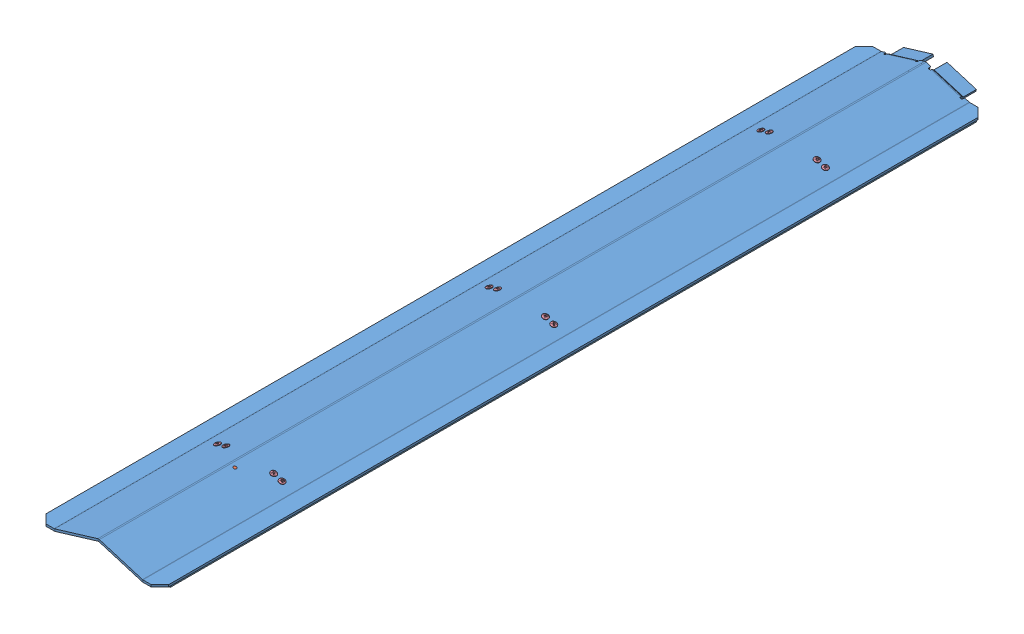
SolidWorks assembly GE-19226, configuration Default. Lengths in mm.
Overall size (177.8 23.82 1219.2).
20 component instances, 5 part files, 39 mates.
Components (placement in the parent):
- GE-19223-1: GE-19223 [Default] at origin size (177.8 22.23 1219.2)
  - GE-19223-1-1: GE-19223-1 [Default] at origin size (177.8 22.23 1219.2)
  - PEM-FH-832-6ZI-1: PEM-FH-832-6ZI [Default] at (7.1934 20.2237 419.1) x (-0.289806 -0.957086 0) z (-0.571052 0.172915 0.802496) size (9.53 6.02 6.02)
- GE-19224-1: GE-19224 [Default] at (0.0601 3.1126 390.525) x (1 -0.000064 0) z (0 0 1) size (106.54 12.92 31.75)
- GE-19224-2: GE-19224 [Default] at (0.0601 3.1126 -3.175) x (1 -0.000064 0) z (0 0 1) size (106.54 12.92 31.75)
- GE-19224-3: GE-19224 [Default] at (0.0601 3.1126 -396.875) x (1 -0.000064 0) z (0 0 1) size (106.54 12.92 31.75)
- rivet_.1563_.1875-.25-1: rivet_.1563_.1875-.25 [Default] at (47.0652 9.4775 390.525) x (-0.569603 0.172476 -0.80362) z (-0.289806 -0.957086 0) size (8.33 8.33 8.57)
- rivet_.1563_.1875-.25-2: rivet_.1563_.1875-.25 [Default] at (-47.0652 9.4775 390.525) x (-0.904542 -0.273895 -0.326781) z (0.289806 -0.957086 0) size (8.33 8.33 8.57)
- rivet_.1563_.1875-.25-3: rivet_.1563_.1875-.25 [Default] at (-34.9102 13.158 -3.175) x (-0.916013 -0.277369 0.289806) z (0.289806 -0.957086 0) size (8.33 8.33 8.57)
- rivet_.1563_.1875-.25-4: rivet_.1563_.1875-.25 [Default] at (-47.0652 9.4775 -3.175) x (-0.916013 -0.277369 0.289806) z (0.289806 -0.957086 0) size (8.33 8.33 8.57)
- rivet_.1563_.1875-.25-5: rivet_.1563_.1875-.25 [Default] at (34.9102 13.158 390.525) x (-0.284635 0.086188 0.954754) z (-0.289806 -0.957086 0) size (8.33 8.33 8.57)
- rivet_.1563_.1875-.25-6: rivet_.1563_.1875-.25 [Default] at (-34.9102 13.158 390.525) x (-0.852981 -0.258283 0.453557) z (0.289806 -0.957086 0) size (8.33 8.33 8.57)
- rivet_.1563_.1875-.25-7: rivet_.1563_.1875-.25 [Default] at (34.9102 13.158 -3.175) x (-0.728247 0.220513 -0.648868) z (-0.289806 -0.957086 0) size (8.33 8.33 8.57)
- rivet_.1563_.1875-.25-9: rivet_.1563_.1875-.25 [Default] at (47.0652 9.4775 -3.175) x (-0.856065 0.259217 -0.447167) z (-0.289806 -0.957086 0) size (8.33 8.33 8.57)
- rivet_.1563_.1875-.25-11: rivet_.1563_.1875-.25 [Default] at (47.0652 9.4775 -396.875) x (-0.934813 0.283061 -0.21448) z (-0.289806 -0.957086 0) size (8.33 8.33 8.57)
- rivet_.1563_.1875-.25-13: rivet_.1563_.1875-.25 [Default] at (34.9102 13.158 -396.875) x (-0.956866 0.289739 0.021408) z (-0.289806 -0.957086 0) size (8.33 8.33 8.57)
- rivet_.1563_.1875-.25-15: rivet_.1563_.1875-.25 [Default] at (-34.9102 13.158 -396.875) x (-0.945179 -0.2862 0.157243) z (0.289806 -0.957086 0) size (8.33 8.33 8.57)
- rivet_.1563_.1875-.25-17: rivet_.1563_.1875-.25 [Default] at (-47.0652 9.4775 -396.875) x (-0.897265 -0.271692 0.347994) z (0.289806 -0.957086 0) size (8.33 8.33 8.57)
- Hook_1_46-1: Hook_1_46 [Default] at (76.2 -1.5875 10.5486) x (0 0 -1) z (1 0 0) size (1168.4 1.59 25.4)
- Hook_1_46-2: Hook_1_46 [Default] at (-76.2 -1.5875 10.5486) x (0 0 1) z (-1 0 0) size (1168.4 1.59 25.4)
Mates (geometry in assembly coordinates):
- Concentric3: concentric: cylinder of GE-19223-1/GE-19223-1-1 through (-46.6971 8.262 390.525) axis (-0.289806 0.957086 0) radius 1.9844; cylinder of GE-19224-1 through (-45.8168 5.3545 390.525) axis (-0.289806 0.957086 0) radius 1.9844
- Coincident1: coincident: plane of GE-19223-1/GE-19223-1-1 through (-63.5 0 609.6) normal (0.289806 -0.957086 0); plane of GE-19224-1 through (-53.2092 3.1161 374.65) normal (-0.289806 0.957086 0)
- Parallel2: parallel: plane of GE-19223-1/GE-19223-1-1 through (1.1159 22.0639 609.6) normal (0 0 1); plane of GE-19224-1 through (-19.6746 10.2184 406.4) normal (0 0 1)
- Concentric4: concentric: cylinder of GE-19223-1/GE-19223-1-1 through (-46.6971 8.262 -3.175) axis (-0.289806 0.957086 0) radius 1.9844; cylinder of GE-19224-2 through (-45.8168 5.3545 -3.175) axis (-0.289806 0.957086 0) radius 1.9844
- Coincident3: coincident: plane of GE-19223-1/GE-19223-1-1 through (-63.5 0 609.6) normal (0.289806 -0.957086 0); plane of GE-19224-2 through (-53.2092 3.1161 -19.05) normal (-0.289806 0.957086 0)
- Parallel3: parallel: plane of assembly; plane of assembly; plane of GE-19224-1 through (-19.6746 10.2184 406.4) normal (0 0 1); plane of GE-19224-2 through (-19.6746 10.2184 12.7) normal (0 0 1)
- Concentric5: concentric: cylinder of GE-19223-1/GE-19223-1-1 through (-46.6971 8.262 -396.875) axis (-0.289806 0.957086 0) radius 1.9844; cylinder of GE-19224-3 through (-45.8168 5.3545 -396.875) axis (-0.289806 0.957086 0) radius 1.9844
- Coincident5: coincident: plane of GE-19223-1/GE-19223-1-1 through (-63.5 0 609.6) normal (0.289806 -0.957086 0); plane of GE-19224-3 through (-53.2092 3.1161 -412.75) normal (-0.289806 0.957086 0)
- Parallel4: parallel: plane of assembly; plane of assembly; plane of GE-19224-2 through (-19.6746 10.2184 12.7) normal (0 0 1); plane of GE-19224-3 through (-19.6746 10.2184 -381) normal (0 0 1)
- Concentric6: concentric: cylinder of GE-19223-1/GE-19223-1-1 through (46.6971 8.262 390.525) axis (0.289806 0.957086 0) radius 1.9844; cylinder of rivet_.1563_.1875-.25-1 through (59.099 49.2191 390.525) axis (0.289806 0.957086 0) radius 1.9844
- Concentric7: concentric: cylinder of GE-19223-1/GE-19223-1-1 through (34.5421 11.9425 390.525) axis (0.289806 0.957086 0) radius 1.9844; cylinder of rivet_.1563_.1875-.25-5 through (46.944 52.8996 390.525) axis (0.289806 0.957086 0) radius 1.9844
- Concentric8: concentric: cylinder of GE-19223-1/GE-19223-1-1 through (-34.5421 11.9425 390.525) axis (-0.289806 0.957086 0) radius 1.9844; cylinder of rivet_.1563_.1875-.25-6 through (-46.944 52.8996 390.525) axis (-0.289806 0.957086 0) radius 1.9844
- Concentric9: concentric: cylinder of GE-19223-1/GE-19223-1-1 through (-46.6971 8.262 390.525) axis (-0.289806 0.957086 0) radius 1.9844; cylinder of rivet_.1563_.1875-.25-2 through (-59.099 49.2191 390.525) axis (-0.289806 0.957086 0) radius 1.9844
- Coincident7: coincident: plane of GE-19223-1/GE-19223-1-1 through (-64.3804 2.9075 609.6) normal (-0.289806 0.957086 0); plane of rivet_.1563_.1875-.25-2 through (-42.9292 9.4029 391.8862) normal (0.289806 -0.957086 0)
- Coincident8: coincident: plane of GE-19223-1/GE-19223-1-1 through (-64.3804 2.9075 609.6) normal (-0.289806 0.957086 0); plane of rivet_.1563_.1875-.25-6 through (-30.989 13.0184 388.6357) normal (0.289806 -0.957086 0)
- Coincident9: coincident: plane of GE-19223-1/GE-19223-1-1 through (0.8804 22.1353 609.6) normal (0.289806 0.957086 0); plane of rivet_.1563_.1875-.25-5 through (35.7278 11.5835 386.5479) normal (-0.289806 -0.957086 0)
- Coincident10: coincident: plane of GE-19223-1/GE-19223-1-1 through (0.8804 22.1353 609.6) normal (0.289806 0.957086 0); plane of rivet_.1563_.1875-.25-1 through (49.0699 7.5435 393.8726) normal (-0.289806 -0.957086 0)
- Concentric10: concentric: cylinder of GE-19223-1/GE-19223-1-1 through (-46.6971 8.262 -3.175) axis (-0.289806 0.957086 0) radius 1.9844; cylinder of rivet_.1563_.1875-.25-4 through (-59.099 49.2191 -3.175) axis (-0.289806 0.957086 0) radius 1.9844
- Concentric12: concentric: cylinder of GE-19223-1/GE-19223-1-1 through (-34.5421 11.9425 -3.175) axis (-0.289806 0.957086 0) radius 1.9844; cylinder of rivet_.1563_.1875-.25-3 through (-46.944 52.8996 -3.175) axis (-0.289806 0.957086 0) radius 1.9844
- Coincident11: coincident: plane of GE-19223-1/GE-19223-1-1 through (-64.3804 2.9075 609.6) normal (-0.289806 0.957086 0); plane of rivet_.1563_.1875-.25-4 through (-42.8814 9.4174 -4.3822) normal (0.289806 -0.957086 0)
- Coincident12: coincident: plane of GE-19223-1/GE-19223-1-1 through (-64.3804 2.9075 609.6) normal (-0.289806 0.957086 0); plane of rivet_.1563_.1875-.25-3 through (-30.7264 13.0979 -4.3822) normal (0.289806 -0.957086 0)
- Concentric13: concentric: cylinder of GE-19223-1/GE-19223-1-1 through (34.5421 11.9425 -3.175) axis (0.289806 0.957086 0) radius 1.9844; cylinder of rivet_.1563_.1875-.25-7 through (46.944 52.8996 -3.175) axis (0.289806 0.957086 0) radius 1.9844
- Coincident13: coincident: plane of GE-19223-1/GE-19223-1-1 through (0.8804 22.1353 609.6) normal (0.289806 0.957086 0); plane of rivet_.1563_.1875-.25-7 through (37.5757 11.0239 -0.4721) normal (-0.289806 -0.957086 0)
- Concentric14: concentric: cylinder of GE-19223-1/GE-19223-1-1 through (46.6971 8.262 -3.175) axis (0.289806 0.957086 0) radius 1.9844; cylinder of rivet_.1563_.1875-.25-9 through (59.099 49.2191 -3.175) axis (0.289806 0.957086 0) radius 1.9844
- Coincident14: coincident: plane of GE-19223-1/GE-19223-1-1 through (0.8804 22.1353 609.6) normal (0.289806 0.957086 0); plane of rivet_.1563_.1875-.25-9 through (50.2632 7.1822 -1.3123) normal (-0.289806 -0.957086 0)
- Concentric15: concentric: cylinder of GE-19223-1/GE-19223-1-1 through (46.6971 8.262 -396.875) axis (0.289806 0.957086 0) radius 1.9844; cylinder of rivet_.1563_.1875-.25-11 through (59.099 49.2191 -396.875) axis (0.289806 0.957086 0) radius 1.9844
- Coincident15: coincident: plane of GE-19223-1/GE-19223-1-1 through (0.8804 22.1353 609.6) normal (0.289806 0.957086 0); plane of rivet_.1563_.1875-.25-11 through (50.5912 7.0828 -395.9816) normal (-0.289806 -0.957086 0)
- Concentric16: concentric: cylinder of GE-19223-1/GE-19223-1-1 through (34.5421 11.9425 -396.875) axis (0.289806 0.957086 0) radius 1.9844; cylinder of rivet_.1563_.1875-.25-13 through (46.944 52.8996 -396.875) axis (0.289806 0.957086 0) radius 1.9844
- Coincident16: coincident: plane of GE-19223-1/GE-19223-1-1 through (0.8804 22.1353 609.6) normal (0.289806 0.957086 0); plane of rivet_.1563_.1875-.25-13 through (38.5281 10.7356 -396.9642) normal (-0.289806 -0.957086 0)
- Concentric17: concentric: cylinder of GE-19223-1/GE-19223-1-1 through (-34.5421 11.9425 -396.875) axis (-0.289806 0.957086 0) radius 1.9844; cylinder of rivet_.1563_.1875-.25-15 through (-46.944 52.8996 -396.875) axis (-0.289806 0.957086 0) radius 1.9844
- Coincident17: coincident: plane of GE-19223-1/GE-19223-1-1 through (-64.3804 2.9075 609.6) normal (-0.289806 0.957086 0); plane of rivet_.1563_.1875-.25-15 through (-30.6049 13.1347 -397.53) normal (0.289806 -0.957086 0)
- Concentric18: concentric: cylinder of GE-19223-1/GE-19223-1-1 through (-46.6971 8.262 -396.875) axis (-0.289806 0.957086 0) radius 1.9844; cylinder of rivet_.1563_.1875-.25-17 through (-59.099 49.2191 -396.875) axis (-0.289806 0.957086 0) radius 1.9844
- Coincident18: coincident: plane of GE-19223-1/GE-19223-1-1 through (-64.3804 2.9075 609.6) normal (-0.289806 0.957086 0); plane of rivet_.1563_.1875-.25-17 through (-42.9595 9.3937 -398.3246) normal (0.289806 -0.957086 0)
- Coincident20: coincident: plane of GE-19223-1/GE-19223-1-1 through (63.5 0 609.6) normal (0 -1 0); plane of Hook_1_46-1 through (76.2 0 10.5486) normal (0 1 0)
- Coincident21: coincident: plane of GE-19223-1/GE-19223-1-1 through (88.9 3.0378 609.6) normal (1 0 0); plane of Hook_1_46-1 through (88.9 0 -573.6514) normal (1 0 0)
- Width1: width: plane of Hook_1_46-1 through (88.9 0 594.7486) normal (0 0 1); plane of Hook_1_46-1 through (88.9 0 -573.6514) normal (0 0 -1); plane of GE-19223-1/GE-19223-1-1 through (-64.2319 4.9428 609.6) normal (0 0 1); plane of GE-19223-1/GE-19223-1-1 through (64.2319 4.9428 -588.5028) normal (0 0 -1)
- Coincident22: coincident: plane of GE-19223-1/GE-19223-1-1 through (-63.5 0 609.6) normal (0 -1 0); plane of Hook_1_46-2 through (-76.2 0 10.5486) normal (0 1 0)
- Coincident23: coincident: plane of GE-19223-1/GE-19223-1-1 through (-88.9 0 609.6) normal (-1 0 0); plane of Hook_1_46-2 through (-88.9 0 594.7486) normal (-1 0 0)
- Width2: width: plane of Hook_1_46-2 through (-88.9 0 594.7486) normal (0 0 1); plane of Hook_1_46-2 through (-88.9 0 -573.6514) normal (0 0 -1); plane of GE-19223-1/GE-19223-1-1 through (-63.6799 3.1196 609.6) normal (0 0 1); plane of GE-19223-1/GE-19223-1-1 through (-64.2319 4.9428 -588.5028) normal (0 0 -1)
